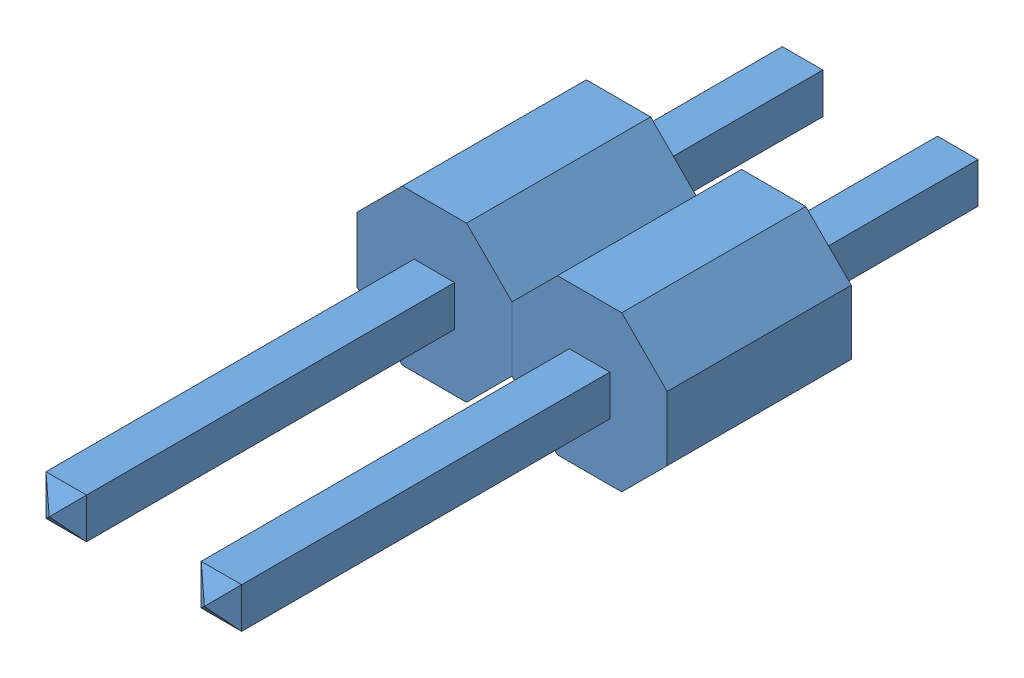
SolidWorks assembly 1X2, configuration Default. Lengths in mm.
Overall size (5.25 2.82 12.38).
3 component instances, 1 part files, 0 mates.
Components (placement in the parent):
- Componente_1-1: Componente_1 [Default] at origin size (5.25 2.82 12.38)
  - Pin-1: Pin [Default] at (1.2601 0 0) x (0 1 0) z (0 0 1) size (2.82 2.73 12.38)
  - Pin-2: Pin [Default] at (-1.2601 0 0) x (0 1 0) z (0 0 1) size (2.82 2.73 12.38)
